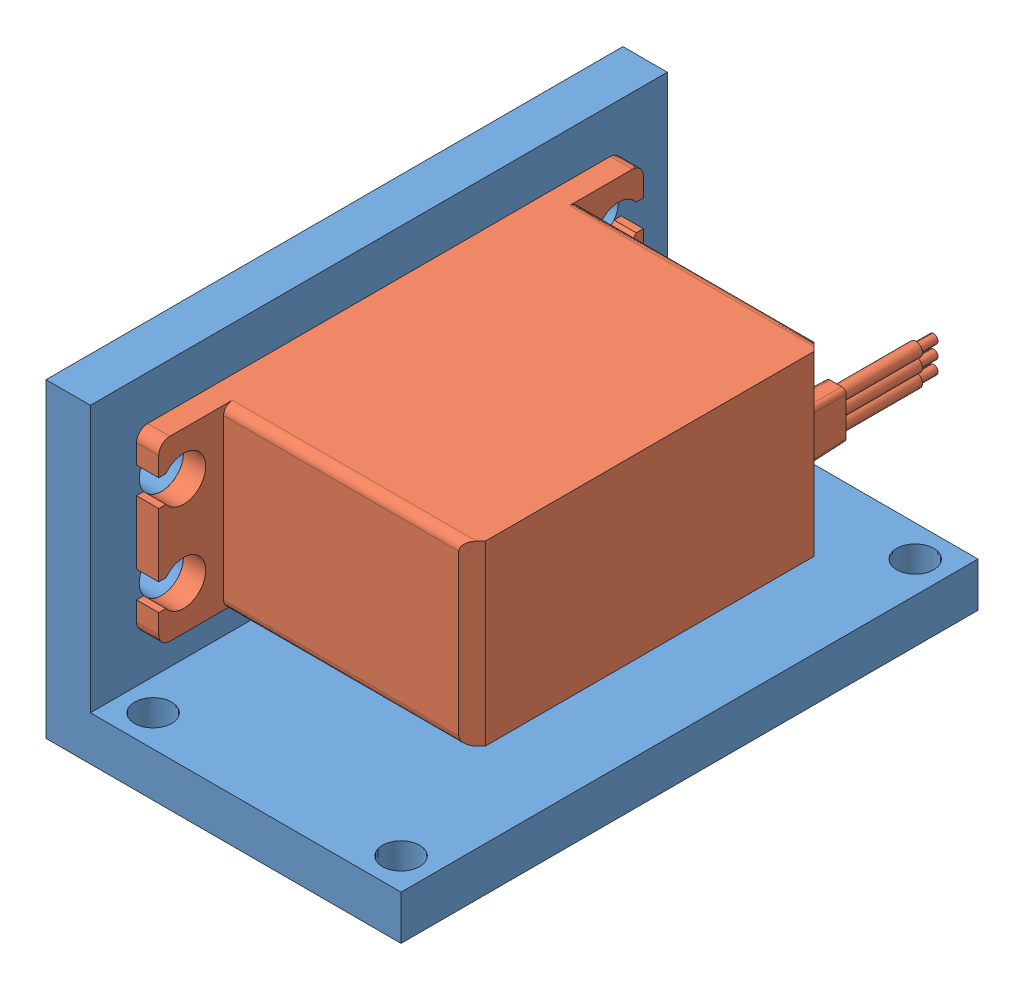
SolidWorks assembly CHADENWOST, configuration Default. Lengths in mm.
Overall size (48 35 67.5).
2 component instances, 2 part files, 3 mates.
Components (placement in the parent):
- SUPPSERVO-1: SUPPSERVO [Default] at (12.8106 22.1814 8.9687) size (40 35 65)
- Servo motor-1: Servo motor [sin servohorn] at (48.3106 42.1814 41.4687) x (0 0 -1) z (0 1 0) size (62.3 43.5 20)
Mates (geometry in assembly coordinates):
- Distance1: distance = 5 mm aligned: plane of SUPPSERVO-1 through (12.8106 57.1814 73.9687) normal (0 1 0); plane of Servo motor-1 through (20.3106 52.1814 61.4687) normal (0 1 0)
- Coincident2: coincident anti-aligned: plane of SUPPSERVO-1 through (17.8106 57.1814 73.9687) normal (1 0 0); plane of Servo motor-1 through (17.8106 33.4314 67.5187) normal (-1 0 0)
- Symmetric1: symmetric aligned: plane of Servo motor-1 through (20.3106 32.1814 61.4687) normal (0 0 1); plane of Servo motor-1 through (20.3106 32.1814 21.4687) normal (0 0 -1)
